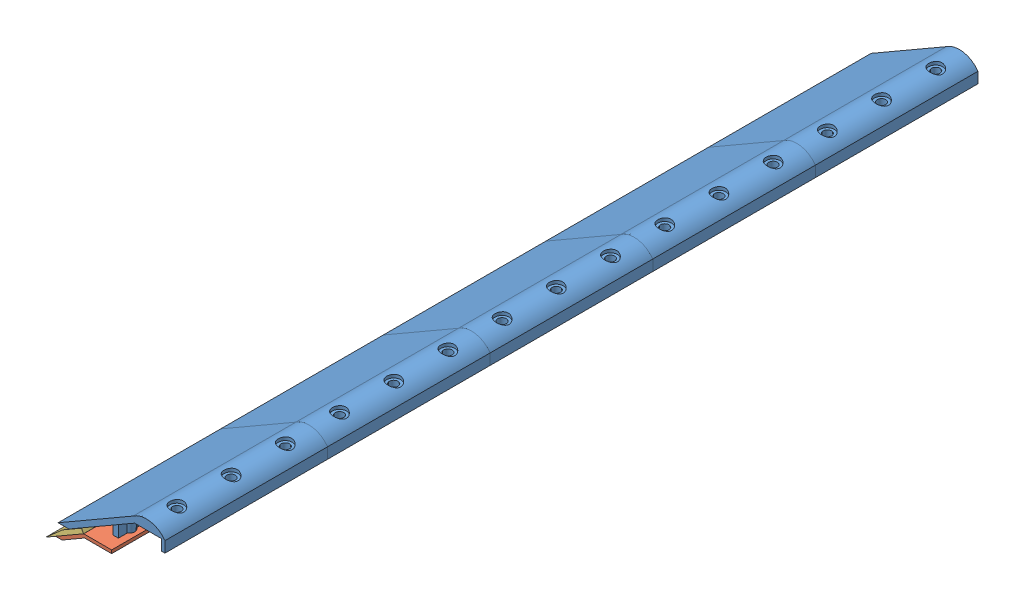
SolidWorks assembly Pala Final con cinta, configuration Predeterminado. Lengths in mm.
Overall size (135.72 60.94 750).
17 component instances, 3 part files, 3 mates.
Components (placement in the parent):
- Pala Final-1: Pala Final [Predeterminado] at (-89.6383 2.5012 300) size (135.72 55.88 750)
  - SoportePala-1: SoportePala [Predeterminado] at (-102.2251 6.5255 0) size (135.72 55.88 150)
    - pala2-1: pala2 [Predeterminado] at (85.8775 17.5121 150) size (98.62 43.88 150)
    - protecto pala-1: protecto pala [Predeterminado] at (39.6775 -17.4879 150) size (110.9 15 150)
  - SoportePala-2: SoportePala [Predeterminado] at (-102.2251 6.5255 150) size (135.72 55.88 150)
    - pala2-1: pala2 [Predeterminado] at (85.8775 17.5121 150) size (98.62 43.88 150)
    - protecto pala-1: protecto pala [Predeterminado] at (39.6775 -17.4879 150) size (110.9 15 150)
  - SoportePala-3: SoportePala [Predeterminado] at (-102.2251 6.5255 300) size (135.72 55.88 150)
    - pala2-1: pala2 [Predeterminado] at (85.8775 17.5121 150) size (98.62 43.88 150)
    - protecto pala-1: protecto pala [Predeterminado] at (39.6775 -17.4879 150) size (110.9 15 150)
  - SoportePala-4: SoportePala [Predeterminado] at (-102.2251 6.5255 450) size (135.72 55.88 150)
    - pala2-1: pala2 [Predeterminado] at (85.8775 17.5121 150) size (98.62 43.88 150)
    - protecto pala-1: protecto pala [Predeterminado] at (39.6775 -17.4879 150) size (110.9 15 150)
  - SoportePala-5: SoportePala [Predeterminado] at (-102.2251 6.5255 600) size (135.72 55.88 150)
    - pala2-1: pala2 [Predeterminado] at (85.8775 17.5121 150) size (98.62 43.88 150)
    - protecto pala-1: protecto pala [Predeterminado] at (39.6775 -17.4879 150) size (110.9 15 150)
- cinta flexy Recogedor-1: cinta flexy Recogedor [Predeterminado] at (-170.4213 -15.5255 750) x (0 0 1) z (-0.5 0.866025 0) size (750 40 4)
Mates (geometry in assembly coordinates):
- Coincidente5: coincident: plane of Pala Final-1/SoportePala-5/protecto pala-1 through (-152.1858 -8.4613 1125) normal (0 0 1); plane of cinta flexy Recogedor-1 through (-189.7418 -22.0613 1125) normal (0 0 1)
- Coincidente6: coincident: plane of Pala Final-1/SoportePala-5/protecto pala-1 through (-152.9897 -5.4613 1125) normal (-0.5 0.866025 0); plane of cinta flexy Recogedor-1 through (-170.4213 -15.5255 750) normal (0.5 -0.866025 0)
- Tangente1: tangent: cylinder of Pala Final-1/SoportePala-5/pala2-1 through (-156.6076 3.359 1100) axis (0 -1 0) radius 1.9844; circle of cinta flexy Recogedor-1
